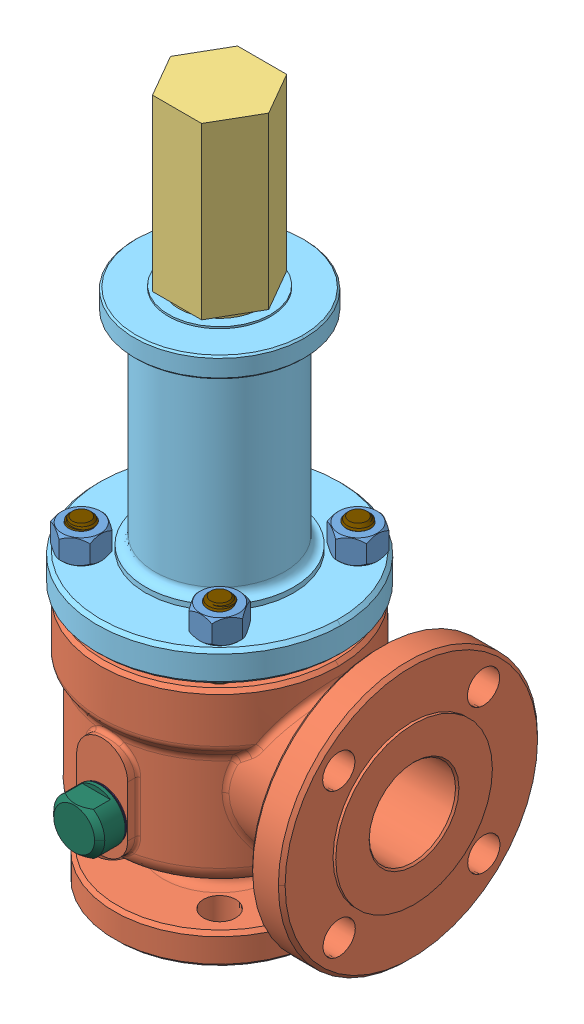
SolidWorks assembly PSV - para armado, configuration Predeterminado. Lengths in mm.
Overall size (187.18 419.01 161.7).
29 component instances, 21 part files, 47 mates.
Components (placement in the parent):
- Tobera D-1: Tobera D [Predeterminado] x (1 0 0) z (0 1 0) size (50.8 50.8 97.01)
- Cuerpo 1-600x2-150 -1: Cuerpo 1-600x2-150  [Predeterminado] at (0 13 0) x (1 0 0) z (0 1 0) size (184.3 152.4 168)
- Guia-1: Guia [Predeterminado] at (0 155.5 0) x (0.998047 0 0.062468) z (0 1 0) size (96 96 41)
- Junta de bonete-1: Junta de bonete [Predeterminado] at (0 155 0) size (96 0.5 96)
- Junta de bonete-2: Junta de bonete [Predeterminado] at (0 166.5 0) size (96 0.5 96)
- Bonete 1x2-1: Bonete 1x2 [Predeterminado] at (0 164 0) x (0.999924 0 0.012345) z (0 1 0) size (144 144 169.75)
- Tornillo de regulación-1: Tornillo de regulación [Predeterminado] at (0 281.2 0) x (-0.56324 0 -0.826294) z (0 1 0) size (23.06 22.92 75)
- Obturador D-1: Obturador D [Predeterminado] at (0 97 0) x (0.624233 0 0.781238) z (0 1 0) size (18 18 17.01)
- Contratuerca-1: Contratuerca [Predeterminado] at (0 333 0) x (0.48879 0 -0.872402) z (0 1 0) size (36.32 28.6 7)
- Porta obturador D-1: Porta obturador D [Predeterminado] at (0 92.2 0) x (0.695537 0 0.71849) z (0 1 0) size (30.5 30.5 94.01)
- Vástago 1x2-1: Vástago 1x2 [Predeterminado] at (0 174.95 0) x (0.837721 0 0.546099) z (0 1 0) size (17.4 17.4 206.42)
- Bolilla 16-2: Bolilla 16 [Predeterminado] at (0 186.55 0) x (0.986843 -0.018715 -0.160592) z (0.156044 0.370189 0.915757) size (9.5 9.5 9.5)
- Platillo de resorte-1: Platillo de resorte [Predeterminado] at (-0.0065 191.4374 0.0103) x (0.533863 0 -0.845571) z (0 1 0) size (55 55 12)
- Platillo de resorte-2: Platillo de resorte [Predeterminado] at (-0.0058 287.1243 0.0107) x (0.480599 0 -0.87694) z (0 -1 0) size (55 55 12)
- Anillo de ajuste D-1: Anillo de ajuste D [Predeterminado] at (0 75.4529 0) x (-0.269168 0 -0.963093) z (0 1 0) size (30.86 30.86 21.01)
- Localizador-1: Localizador [Predeterminado] at (0 83 38.5) x (0.923728 0.383049 0) z (0 0 -1) size (8.21 8.21 45.01)
- Tornillo localizador-1: Tornillo localizador [Predeterminado] at (0 83 51.5) x (-1 0 0) z (0 0 1) size (30.01 30.02 34.01)
- Contratuerca 5-16 x 6-1: Contratuerca 5-16 x 6 [Predeterminado] at (0 83 51.5) x (0.923728 0.383049 0) z (0 0 -1) size (13.87 13.87 6.74)
- Junta de localizador-1: Junta de localizador [Predeterminado] at (0 83 69) x (0.923728 0.383049 0) z (0.383049 -0.923728 0) size (29 0.5 29)
- Esparrago 9-16-1: Esparrago 9-16 [Predeterminado] at (40.6586 134.4184 40.6586) x (0.675391 0 -0.73746) z (0.73746 0 0.675391) size (15.95 65.75 15.95)
- Esparrago 9-16-2: Esparrago 9-16 [Predeterminado] at (40.6586 134.4184 -40.6586) x (-0.73746 0 -0.675391) z (0.675391 0 -0.73746) size (15.95 65.75 15.95)
- Esparrago 9-16-3: Esparrago 9-16 [Predeterminado] at (-40.6586 134.4184 -40.6586) x (-0.675391 0 0.73746) z (-0.73746 0 -0.675391) size (15.95 65.75 15.95)
- Esparrago 9-16-4: Esparrago 9-16 [Predeterminado] at (-40.6586 134.4184 40.6586) x (0.73746 0 0.675391) z (-0.675391 0 0.73746) size (15.95 65.75 15.95)
- Tuerca 2H- 9-16-1: Tuerca 2H- 9-16 [Predeterminado] at (40.6586 189.15 40.6586) x (0.999906 0 -0.013693) z (0.013693 0 0.999906) size (29.21 14.3 23)
- Tuerca 2H- 9-16-2: Tuerca 2H- 9-16 [Predeterminado] at (40.6586 189.15 -40.6586) x (-0.013693 0 -0.999906) z (0.999906 0 -0.013693) size (29.21 14.3 23)
- Tuerca 2H- 9-16-3: Tuerca 2H- 9-16 [Predeterminado] at (-40.6586 189.15 -40.6586) x (-0.999906 0 0.013693) z (-0.013693 0 -0.999906) size (29.21 14.3 23)
- Tuerca 2H- 9-16-4: Tuerca 2H- 9-16 [Predeterminado] at (-40.6586 189.15 40.6586) x (0.013693 0 0.999906) z (-0.999906 0 0.013693) size (29.21 14.3 23)
- Resorte std-1: Resorte std [Predeterminado] at origin size (54.35 97.92 54.21)
- Tapa-1: Tapa [Predeterminado] at (0 319 0) size (57.74 102.99 50)
Mates (geometry in assembly coordinates):
- Coincidente2: coincident anti-aligned: plane of Tobera D-1 through (-24.4 0 24.4168) normal (0 -1 0)
- Coincidente4: coincident anti-aligned: plane of Tobera D-1 through (0 0 0) normal (0 0 -1)
- Coincidente5: coincident aligned: plane of Tobera D-1 through (0 0 0) normal (1 0 0)
- Coincidente6: coincident anti-aligned: plane of Tobera D-1 through (-24.9 13 24.9165) normal (0 1 0); plane of Cuerpo 1-600x2-150 -1 through (-59.9 13 59.918) normal (0 -1 0)
- Concéntrica1: concentric anti-aligned: cylinder of Tobera D-1 through (0 1 0) axis (0 1 0) radius 25.4; cylinder of Cuerpo 1-600x2-150 -1 through (0 21 0) axis (0 -1 0) radius 17.6
- Coincidente7: coincident anti-aligned: plane of Cuerpo 1-600x2-150 -1 through (49.062 155 -48.1) normal (0 1 0); plane of Junta de bonete-1 through (0 155 0) normal (0 -1 0)
- Concéntrica2: concentric aligned: cylinder of Cuerpo 1-600x2-150 -1 through (0 160 0) axis (0 -1 0) radius 48.1; cylinder of Junta de bonete-1 through (0 155.5 0) axis (0 -1 0) radius 40
- Coincidente8: coincident anti-aligned: plane of Guia-1 through (-50.9647 155.5 45.8659) normal (0 -1 0); plane of Junta de bonete-1 through (0 155.5 0) normal (0 1 0)
- Concéntrica3: concentric anti-aligned: cylinder of Cuerpo 1-600x2-150 -1 through (0 160 0) axis (0 -1 0) radius 48.1; cylinder of Guia-1 through (0 155.5 0) axis (0 1 0) radius 48
- Coincidente9: coincident anti-aligned: plane of Guia-1 through (-50.9647 166.5 45.8659) normal (0 1 0); plane of Junta de bonete-2 through (0 166.5 0) normal (0 -1 0)
- Concéntrica4: concentric anti-aligned: cylinder of Guia-1 through (0 155.5 0) axis (0 1 0) radius 48; cylinder of Junta de bonete-2 through (0 167 0) axis (0 -1 0) radius 48
- Coincidente10: coincident anti-aligned: plane of Junta de bonete-2 through (0 167 0) normal (0 1 0); plane of Bonete 1x2-1 through (30.9976 167 0.3827) normal (0 -1 0)
- Concéntrica5: concentric aligned: cylinder of Guia-1 through (0 155.5 0) axis (0 1 0) radius 48; cylinder of Bonete 1x2-1 through (0 163.995 0) axis (0 1 0) radius 48.1
- Concéntrica6: concentric anti-aligned: cylinder of Cuerpo 1-600x2-150 -1 through (40.6586 159.65 -40.6586) axis (0 -1 0) radius 7.1437; cylinder of Bonete 1x2-1 through (40.6586 182 -40.6586) axis (0 1 0) radius 8.25
- Concéntrica7: concentric aligned: cylinder of Bonete 1x2-1 through (0 163.995 0) axis (0 1 0) radius 11.11; cylinder of Tornillo de regulación-1 through (0 284.2001 0) axis (0 1 0) radius 9.5
- Coincidente11: coincident anti-aligned: plane of Bonete 1x2-1 through (-17.2592 333 16.8382) normal (0 1 0); plane of Contratuerca-1 through (5.6148 333 19.1935) normal (0 -1 0)
- Concéntrica8: concentric anti-aligned: cylinder of Tornillo de regulación-1 through (0 281.2 0) axis (0 -1 0) radius 5.25; cylinder of Contratuerca-1 through (0 333 0) axis (0 1 0) radius 10.25
- Concéntrica9: concentric anti-aligned: cylinder of Guia-1 through (0 125.5 0) axis (0 1 0) radius 7.2; cylinder of Porta obturador D-1 through (0 171.2 0) axis (0 -1 0) radius 7.15
- Concéntrica10: concentric aligned: cylinder of Obturador D-1 through (0 102.1998 0) axis (0 -1 0) radius 9; cylinder of Porta obturador D-1 through (0 103.2 0) axis (0 -1 0) radius 9.15
- Distancia2: distance = 0.2 mm anti-aligned: plane of Obturador D-1 through (-1.3008 103 11.5355) normal (0 1 0); plane of Porta obturador D-1 through (-0.3415 103.2 13.0656) normal (0 -1 0)
- Concéntrica11: concentric anti-aligned: cylinder of Tornillo de regulación-1 through (0 281.2 0) axis (0 -1 0) radius 5.25; cylinder of Vástago 1x2-1 through (0 199.6574 0) axis (0 1 0) radius 4.75
- Concéntrica12: concentric: cylinder of Porta obturador D-1 through (0 180.7 0) axis (0 -1 0) radius 6.25; sphere of Bolilla 16-2
- Coincidente15: coincident anti-aligned: plane of Cuerpo 1-600x2-150 -1 through (0 13 0) normal (0 0 -1)
- Concéntrica13: concentric aligned: cylinder of Platillo de resorte-1 through (0 191.4374 0) axis (0 1 0) radius 5; cylinder of Vástago 1x2-1 through (0 199.6574 0) axis (0 1 0) radius 4.75
- Concéntrica17: concentric aligned: cylinder of Tobera D-1 through (0 87 0) axis (0 1 0) radius 8.5; cylinder of Anillo de ajuste D-1 through (0 76.4527 0) axis (0 1 0) radius 8.6
- Concéntrica18: concentric anti-aligned: cylinder of Localizador-1 through (0 83 38.5) axis (0 0 -1) radius 4; cylinder of Tornillo localizador-1 through (0 83 52.4999) axis (0 0 1) radius 3.5
- Concéntrica19: concentric aligned: cylinder of Localizador-1 through (0 83 38.5) axis (0 0 -1) radius 4; line of Contratuerca 5-16 x 6-1 through (0 83 51.5) axis (0 0 -1)
- Coincidente23: coincident anti-aligned: plane of Tornillo localizador-1 through (8.5 91.5135 51.5) normal (0 0 -1); plane of Contratuerca 5-16 x 6-1 through (-7.7533 86.2208 51.5) normal (0 0 1)
- Coincidente24: coincident anti-aligned: plane of Tornillo localizador-1 through (14 97 69.5) normal (0 0 -1); plane of Junta de localizador-1 through (0 83 69.5) normal (0 0 1)
- Concéntrica20: concentric anti-aligned: cylinder of Tornillo localizador-1 through (0 83 52.5001) axis (0 0 1) radius 9.5; cylinder of Junta de localizador-1 through (0 83 69.5) axis (0 0 -1) radius 9.5
- Concéntrica21: concentric anti-aligned: cylinder of Cuerpo 1-600x2-150 -1 through (0 83 69) axis (0 0 -1) radius 8.75; cylinder of Tornillo localizador-1 through (0 83 52.5001) axis (0 0 1) radius 9.5
- Coincidente25: coincident anti-aligned: plane of Cuerpo 1-600x2-150 -1 through (-15 60.4 69) normal (0 0 1); plane of Junta de localizador-1 through (0 83 69) normal (0 0 -1)
- Concéntrica22: concentric aligned: cylinder of Cuerpo 1-600x2-150 -1 through (40.6586 159.65 40.6586) axis (0 -1 0) radius 7.1437; cylinder of Esparrago 9-16-1 through (40.6586 199.4184 40.6586) axis (0 -1 0) radius 7.15
- Concéntrica25: concentric anti-aligned: cylinder of Bonete 1x2-1 through (40.6586 182 40.6586) axis (0 1 0) radius 8.25; cylinder of Tuerca 2H- 9-16-1 through (40.6586 196.3 40.6586) axis (0 -1 0) radius 6.65
- Coincidente26: coincident anti-aligned: plane of Bonete 1x2-1 through (-70.8591 182 69.1515) normal (0 1 0); plane of Tuerca 2H- 9-16-1 through (53.9365 182 40.4768) normal (0 -1 0)
- Distancia10: distance = 4.4 mm anti-aligned: sphere of Bolilla 16-2; plane of Porta obturador D-1 through (-0.2333 186.2 8.9246) normal (0 1 0)
- Coincidente27: coincident aligned: cone of Vástago 1x2-1 through (0 193.6574 0) axis (0 1 0); cone of Platillo de resorte-1 through (0 191.4074 0) axis (0 1 0)
- Distancia11: distance = 0.75 mm anti-aligned: plane of Vástago 1x2-1 through (-9.5526 186.95 2.0186) normal (0 -1 0); plane of Porta obturador D-1 through (-0.2333 186.2 8.9246) normal (0 1 0)
- Coincidente29: coincident aligned: cone of Tornillo de regulación-1 through (0 279.6816 0) axis (0 -1 0); cone of Platillo de resorte-2 through (0 287.1543 0) axis (0 -1 0)
- Distancia13: distance = 23.2 mm aligned: plane of Bonete 1x2-1 through (-17.2592 333 16.8382) normal (0 1 0); plane of Tornillo de regulación-1 through (11.1611 356.2 1.9528) normal (0 1 0)
- EnPosición1: in place: plane of Resorte std-1 through (0 0 0) normal (0 0 1); moOrthogonalPlaneRef_w of Resorte std-1 through (0 0 0) normal (0 1 0); plane of Resorte std-1 through (0 0 0) normal (1 0 0); unknown of Resorte std-1
- Coincidente30: coincident aligned: 
- Coincidente31: coincident aligned: plane of Resorte std-1 through (0 0 0) normal (0 1 0)
- Coincidente32: coincident anti-aligned: plane of Resorte std-1 through (0 0 0) normal (1 0 0)
- Distancia14: distance = 0 mm anti-aligned: plane of Tobera D-1 through (-7.4 97 7.548) normal (0 1 0); plane of Obturador D-1 through (-1.3008 97 11.5355) normal (0 -1 0)
- Concéntrica26: concentric aligned: cylinder of Bonete 1x2-1 through (0 316 0) axis (0 1 0) radius 30; cylinder of Tapa-1 through (0 317 0) axis (0 1 0) radius 24
- Coincidente30: coincident anti-aligned: plane of Bonete 1x2-1 through (-30.3682 317 29.6424) normal (0 1 0); plane of Tapa-1 through (0 317 0) normal (0 -1 0)
